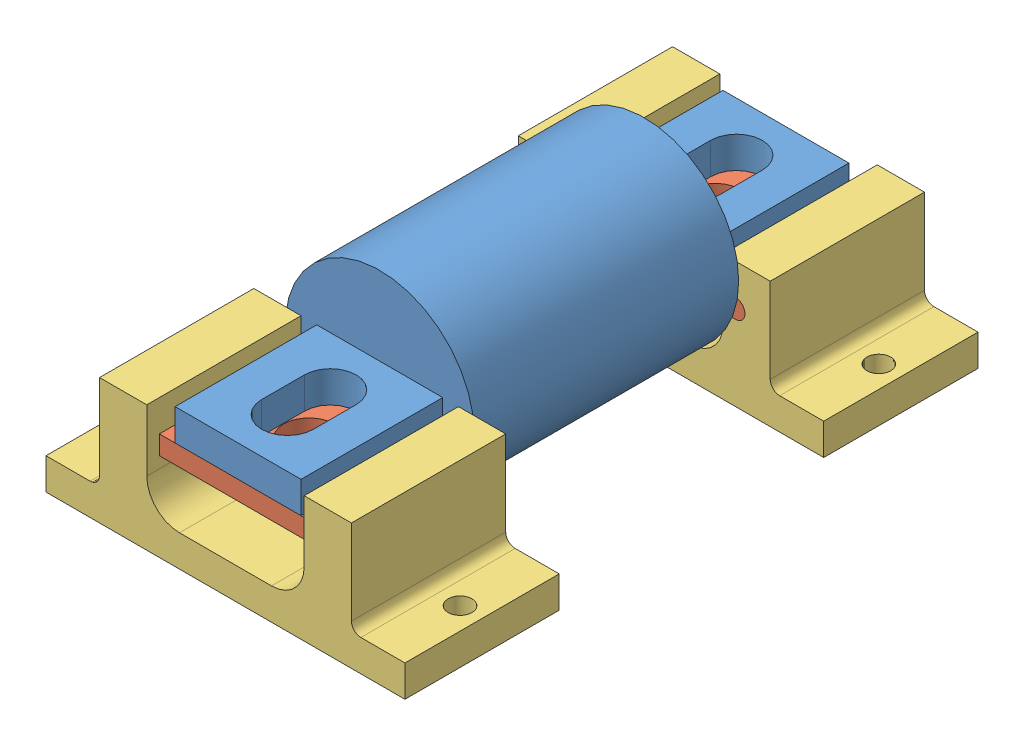
SolidWorks assembly HV Fusing, configuration Default. Lengths in mm.
Overall size (72.39 41.27 115.57).
5 component instances, 3 part files, 12 mates.
Components (placement in the parent):
- HV Fuse-1: HV Fuse [Default] at (30.4773 64.4678 85.8661) size (38.1 38.1 110.49)
- HV Fuseholder Plate-1: HV Fuseholder Plate [Default] at (30.4773 59.3878 112.5361) size (40.64 3.81 28.57)
- HV Fuseholder Plate-2: HV Fuseholder Plate [Default] at (30.4773 59.3878 30.6211) size (40.64 3.81 28.57)
- HV Fuseholder-1: HV Fuseholder [Default] at (30.4773 67.6428 112.5361) size (72.39 25.4 31.12)
- HV Fuseholder-2: HV Fuseholder [Default] at (30.4773 67.6428 59.1961) x (-1 0 0) z (0 0 -1) size (72.39 25.4 31.12)
Mates (geometry in assembly coordinates):
- Coincident1: coincident: plane of HV Fuseholder Plate-1 through (12.0623 61.2928 141.1111) normal (0 1 0); line of HV Fuseholder-1 through (14.6023 61.2928 141.1111) axis (0 0 -1)
- Coincident2: coincident anti-aligned: plane of HV Fuse-1 through (30.4773 61.2928 85.8661) normal (0 -1 0); plane of HV Fuseholder Plate-1 through (12.0623 61.2928 141.1111) normal (0 1 0)
- Coincident3: coincident aligned: plane of HV Fuse-1 through (30.4773 64.4678 85.8661) normal (1 0 0); plane of HV Fuseholder Plate-1 through (30.4773 59.3878 112.5361) normal (1 0 0)
- Coincident4: coincident aligned: plane of HV Fuse-1 through (30.4773 64.4678 85.8661) normal (1 0 0); plane of HV Fuseholder-1 through (30.4773 67.6428 112.5361) normal (1 0 0)
- Coincident5: coincident anti-aligned: plane of HV Fuse-1 through (30.4773 64.4678 112.5361) normal (0 0 1); plane of HV Fuseholder Plate-1 through (12.0623 59.3878 112.5361) normal (0 0 -1)
- Coincident6: coincident anti-aligned: plane of HV Fuseholder Plate-1 through (12.0623 59.3878 141.1111) normal (0 0 1); plane of HV Fuseholder-1 through (3.1723 50.4978 141.1111) normal (0 0 -1)
- Coincident10: coincident aligned: plane of HV Fuse-1 through (30.4773 64.4678 85.8661) normal (1 0 0); plane of HV Fuseholder Plate-2 through (30.4773 59.3878 30.6211) normal (1 0 0)
- Coincident11: coincident anti-aligned: plane of HV Fuse-1 through (30.4773 64.4678 85.8661) normal (1 0 0); plane of HV Fuseholder-2 through (30.4773 67.6428 44.5469) normal (-1 0 0)
- Coincident13: coincident anti-aligned: plane of HV Fuse-1 through (30.4773 61.2928 85.8661) normal (0 -1 0); plane of HV Fuseholder Plate-2 through (12.0623 61.2928 59.1961) normal (0 1 0)
- Coincident14: coincident anti-aligned: plane of HV Fuse-1 through (30.4773 64.4678 59.1961) normal (0 0 -1); plane of HV Fuseholder Plate-2 through (12.0623 59.3878 59.1961) normal (0 0 1)
- Coincident16: coincident: plane of HV Fuseholder Plate-2 through (12.0623 61.2928 59.1961) normal (0 1 0); line of HV Fuseholder-2 through (46.3523 61.2928 30.6211) axis (0 0 1)
- Coincident17: coincident anti-aligned: plane of HV Fuseholder Plate-2 through (12.0623 59.3878 30.6211) normal (0 0 -1); plane of HV Fuseholder-2 through (57.7823 50.4978 30.6211) normal (0 0 1)
